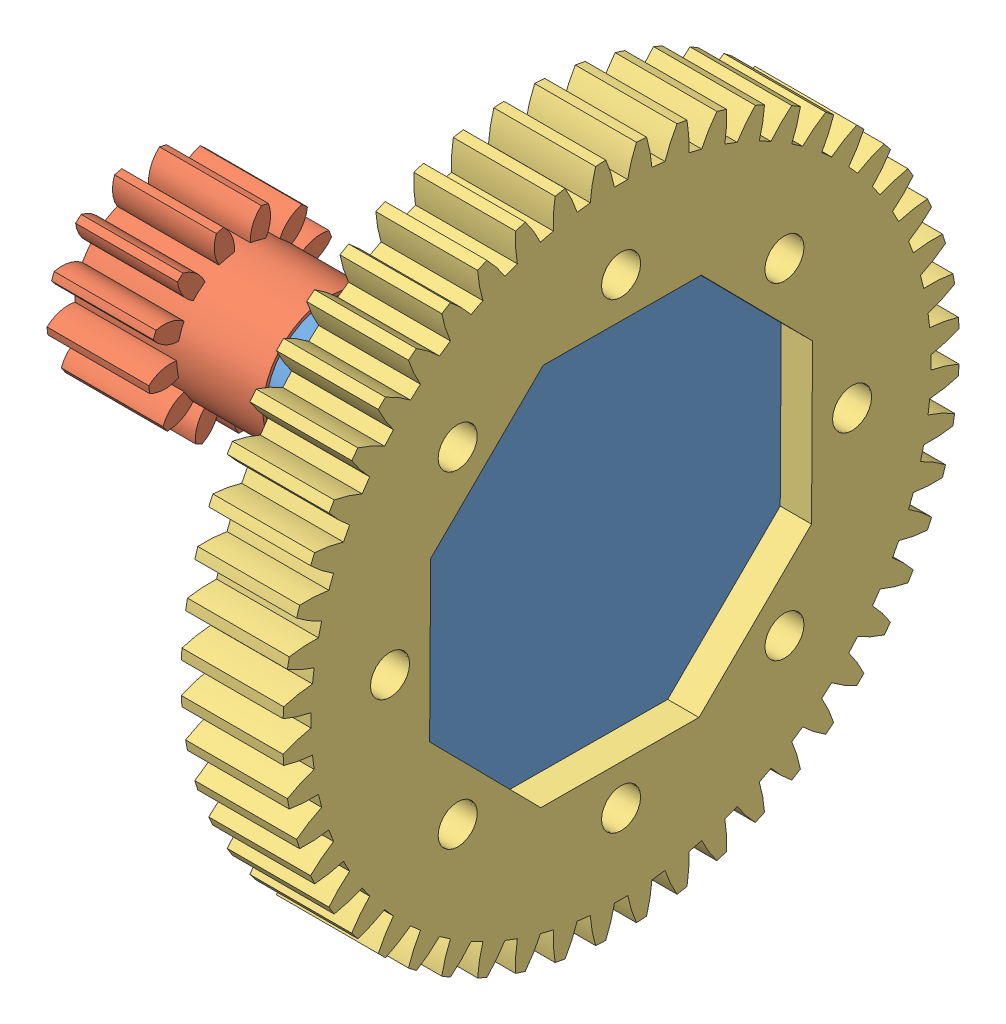
SolidWorks assembly CopleEngrane, configuration Predeterminado. Lengths in mm.
Overall size (30.68 43.16 43.16).
3 component instances, 3 part files, 4 mates.
Components (placement in the parent):
- Cople-1: Cople [Predeterminado] at (4.4173 -10.5202 49.0087) x (0 0 -1) z (0 -1 0) size (34.5 28.68 34.5)
- Gear 13T-1: Gear 13T [Default] at (-13.2577 -10.5202 49.0087) x (-1 0 0) z (0 0 -1) size (12 11.88 11.96)
- Gear_52T-1: Gear_52T [Predeterminado] at (4.4173 -10.5202 49.0087) size (6.5 43.16 43.16)
Mates (geometry in assembly coordinates):
- Concéntrica3: concentric: cylinder of Cople-1 through (-19.7577 -10.5202 49.0087) axis (1 0 0) radius 2.5; cylinder of Gear 13T-1 through (-19.7577 -10.5202 49.0087) axis (1 0 0) radius 4.199
- Coincidente2: coincident: plane of Cople-1 through (-19.7577 -10.5202 49.0087) normal (-1 0 0); plane of Gear 13T-1 through (-19.7577 -10.5202 49.0087) normal (-1 0 0)
- Concéntrica4: concentric: cylinder of Cople-1 through (8.9173 -10.5202 49.0087) axis (-1 0 0) radius 17.25; cylinder of Gear_52T-1 through (4.4173 -10.5202 49.0087) axis (-1 0 0) radius 17.3
- Coincidente3: coincident: plane of Cople-1 through (8.9173 -10.5202 49.0087) normal (1 0 0); plane of Gear_52T-1 through (8.9173 -8.5202 49.0087) normal (-1 0 0)
